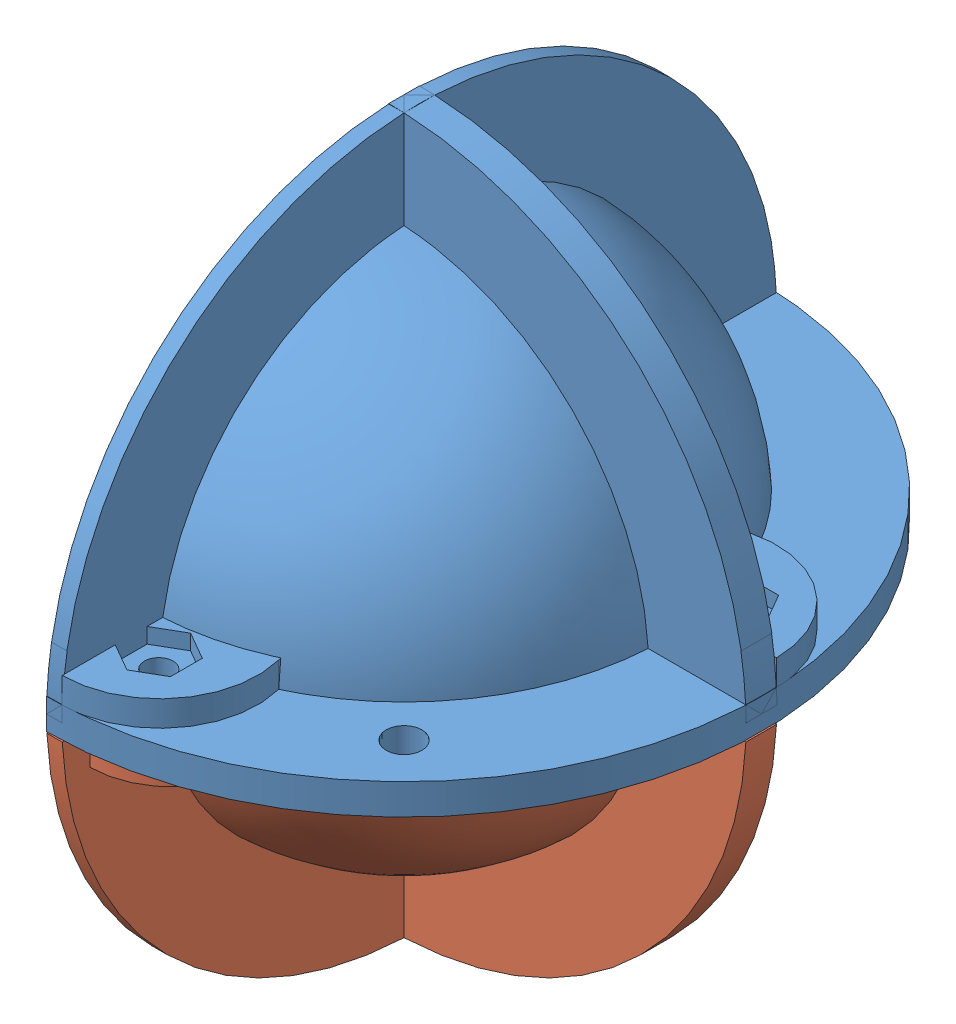
SolidWorks assembly old_drifter_housing_assembly, configuration Default. Lengths in mm.
Overall size (35 70 70).
2 component instances, 2 part files, 3 mates.
Components (placement in the parent):
- enclosure_half_one_MEASUREMENT-1: enclosure_half_one_MEASUREMENT [Default] at origin size (35 58.98 70)
- enclosure_half_two_MEASUREMENT-1: enclosure_half_two_MEASUREMENT [Default] x (1 0 0) z (0 0 -1) size (34.96 58.98 69.92)
Mates (geometry in assembly coordinates):
- Coincident3: coordinate: point of enclosure_half_one_MEASUREMENT-1
- Coincident4: coincident aligned: circle of enclosure_half_one_MEASUREMENT-1; circle of enclosure_half_two_MEASUREMENT-1
- Parallel1: parallel anti-aligned: plane of enclosure_half_one_MEASUREMENT-1 through (0 -1.5 0) normal (0 -1 0); plane of enclosure_half_two_MEASUREMENT-1 through (-24.2386 -1.65 1.5) normal (0 1 0)
